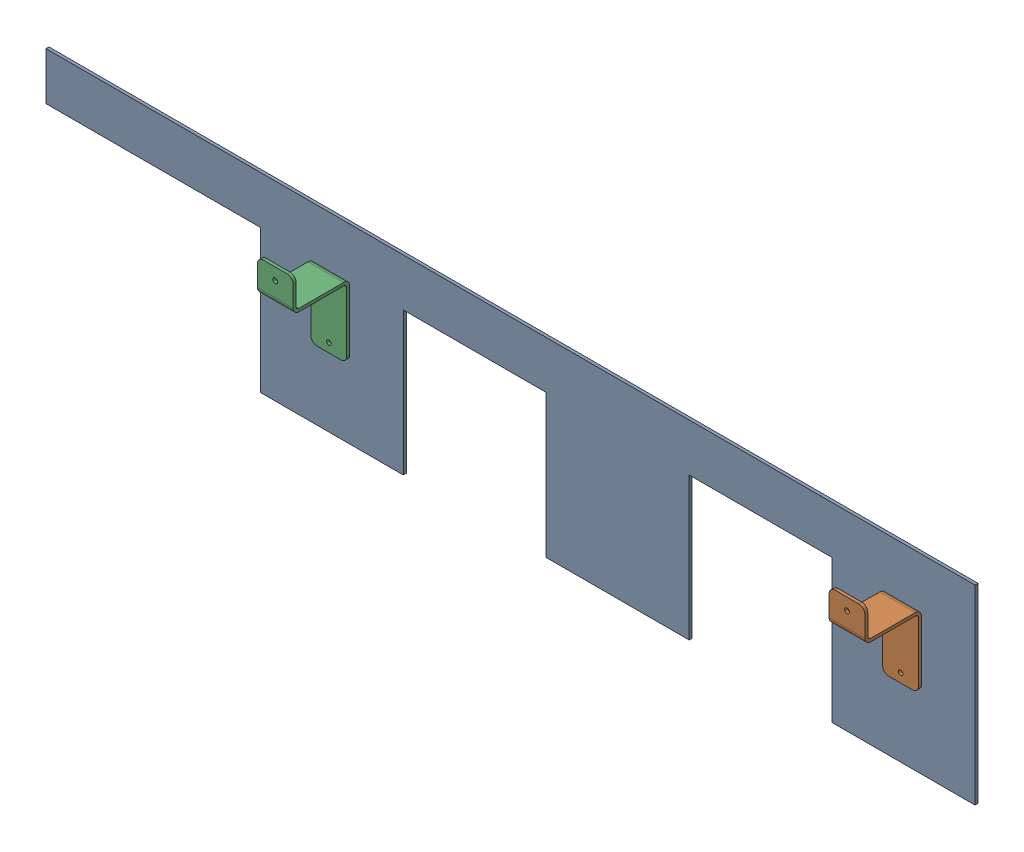
SolidWorks assembly GE-16131_ASM, configuration Default. Lengths in mm.
Overall size (990.6 203.2 63.5).
3 component instances, 2 part files, 0 mates.
Components (placement in the parent):
- GE-16132-1: GE-16132 [Default] at origin size (990.6 203.2 3.17)
- GE-16135-1: GE-16135 [Default] at (419.1 50.8 3.175) x (1 0 0) z (0 1 0) size (38.1 60.32 107.95)
- GE-16135-2: GE-16135 [Default] at (-190.5 50.8 3.175) x (1 0 0) z (0 1 0) size (38.1 60.32 107.95)
